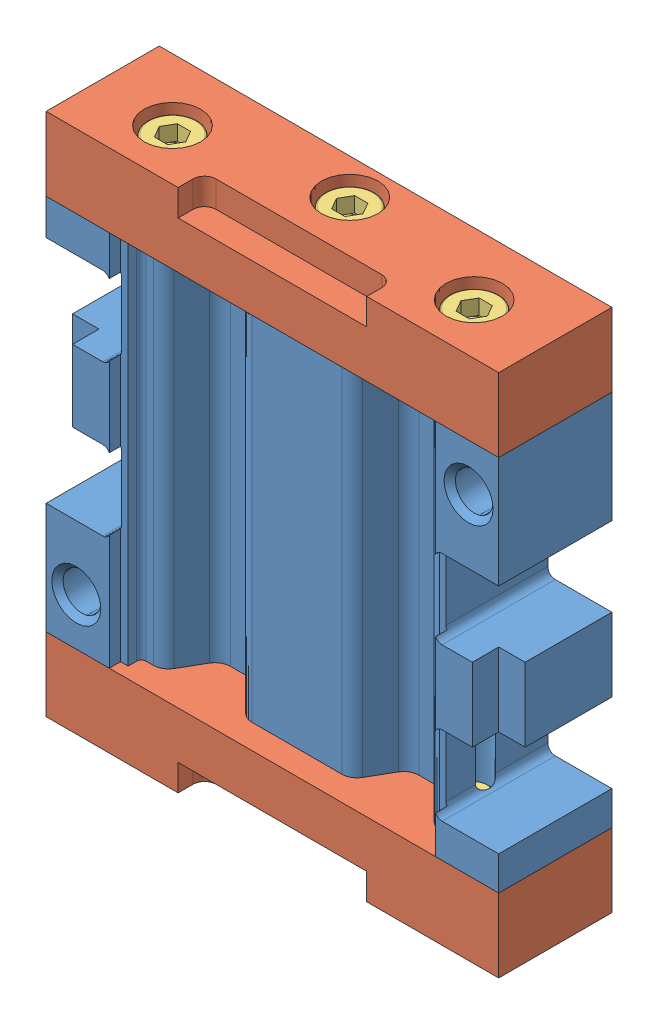
SolidWorks assembly СборкаВерх, configuration По умолчанию. Lengths in mm.
Overall size (120 139 30).
9 component instances, 3 part files, 18 mates.
Components (placement in the parent):
- Пуансон-1: Пуансон [По умолчанию] at origin size (120 100 30)
- БоковинаПуасона-1: БоковинаПуасона [По умолчанию] at (120 100 -30) x (-1 0 0) z (0 0 -1) size (120 19.5 30)
- БоковинаПуасона-3: БоковинаПуасона [По умолчанию] at (0 0 -30) x (1 0 0) z (0 0 -1) size (120 19.5 30)
- socket head cap screw_iso-1: socket head cap screw_iso [ISO 4762 M8 x 16 - 16N] at (100 -17.5 -13.5) x (0 1 0) z (0 0 1) size (24 13 13)
- socket head cap screw_iso-2: socket head cap screw_iso [ISO 4762 M8 x 16 - 16N] at (60 -17.5 -20.5) x (0 1 0) z (0 0 1) size (24 13 13)
- socket head cap screw_iso-3: socket head cap screw_iso [ISO 4762 M8 x 16 - 16N] at (20 -17.5 -13.5) x (0 1 0) z (0 0 1) size (24 13 13)
- socket head cap screw_iso-4: socket head cap screw_iso [ISO 4762 M8 x 16 - 16N] at (20 117.5 -13.5) x (0 -1 0) z (0 0 1) size (24 13 13)
- socket head cap screw_iso-5: socket head cap screw_iso [ISO 4762 M8 x 16 - 16N] at (60 117.5 -20.5) x (0 -1 0) z (0 0 1) size (24 13 13)
- socket head cap screw_iso-6: socket head cap screw_iso [ISO 4762 M8 x 16 - 16N] at (100 117.5 -13.5) x (0 -1 0) z (0 0 1) size (24 13 13)
Mates (geometry in assembly coordinates):
- Совпадение1: coincident anti-aligned: plane of Пуансон-1 through (0 0 0) normal (0 -1 0); plane of БоковинаПуасона-3 through (0 0 -30) normal (0 1 0)
- Совпадение2: coincident anti-aligned: plane of Пуансон-1 through (0 100 0) normal (0 1 0); plane of БоковинаПуасона-1 through (120 100 -30) normal (0 -1 0)
- Концентричный1: concentric aligned: cylinder of Пуансон-1 through (100 77.75 -13.5) axis (0 1 0) radius 4; cylinder of БоковинаПуасона-1 through (100 100 -13.5) axis (0 1 0) radius 4.5
- Концентричный2: concentric aligned: cylinder of Пуансон-1 through (20 77.75 -13.5) axis (0 1 0) radius 4; cylinder of БоковинаПуасона-1 through (20 100 -13.5) axis (0 1 0) radius 4.5
- Концентричный3: concentric aligned: cylinder of Пуансон-1 through (100 22.25 -13.5) axis (0 -1 0) radius 4; cylinder of БоковинаПуасона-3 through (100 0 -13.5) axis (0 -1 0) radius 4.5
- Концентричный4: concentric aligned: cylinder of Пуансон-1 through (20 22.25 -13.5) axis (0 -1 0) radius 4; cylinder of БоковинаПуасона-3 through (20 0 -13.5) axis (0 -1 0) radius 4.5
- Концентричный5: concentric aligned: cylinder of БоковинаПуасона-3 through (100 0 -13.5) axis (0 -1 0) radius 4.5; cylinder of socket head cap screw_iso-1 through (100 -49.25 -13.5) axis (0 -1 0) radius 6.5
- Совпадение3: coincident anti-aligned: plane of БоковинаПуасона-3 through (100 -9.5 -13.5) normal (0 -1 0); plane of socket head cap screw_iso-1 through (93.5 -9.5 -13.5) normal (0 1 0)
- Концентричный6: concentric aligned: cylinder of БоковинаПуасона-3 through (60 0 -20.5) axis (0 -1 0) radius 4.5; cylinder of socket head cap screw_iso-2 through (60 -49.25 -20.5) axis (0 -1 0) radius 6.5
- Совпадение4: coincident anti-aligned: plane of БоковинаПуасона-3 through (60 -9.5 -20.5) normal (0 -1 0); plane of socket head cap screw_iso-2 through (53.5 -9.5 -20.5) normal (0 1 0)
- Концентричный7: concentric aligned: cylinder of БоковинаПуасона-3 through (20 0 -13.5) axis (0 -1 0) radius 4.5; cylinder of socket head cap screw_iso-3 through (20 -49.25 -13.5) axis (0 -1 0) radius 6.5
- Совпадение5: coincident anti-aligned: plane of БоковинаПуасона-3 through (20 -9.5 -13.5) normal (0 -1 0); plane of socket head cap screw_iso-3 through (13.5 -9.5 -13.5) normal (0 1 0)
- Концентричный8: concentric aligned: cylinder of БоковинаПуасона-1 through (20 109.5 -13.5) axis (0 1 0) radius 7.5; cylinder of socket head cap screw_iso-4 through (20 149.25 -13.5) axis (0 1 0) radius 6.5
- Совпадение6: coincident anti-aligned: plane of БоковинаПуасона-1 through (20 109.5 -13.5) normal (0 1 0); plane of socket head cap screw_iso-4 through (26.5 109.5 -13.5) normal (0 -1 0)
- Концентричный9: concentric aligned: cylinder of БоковинаПуасона-1 through (60 100 -20.5) axis (0 1 0) radius 4.5; cylinder of socket head cap screw_iso-5 through (60 149.25 -20.5) axis (0 1 0) radius 6.5
- Совпадение7: coincident anti-aligned: plane of БоковинаПуасона-1 through (60 109.5 -20.5) normal (0 1 0); plane of socket head cap screw_iso-5 through (66.5 109.5 -20.5) normal (0 -1 0)
- Концентричный10: concentric aligned: cylinder of БоковинаПуасона-1 through (100 109.5 -13.5) axis (0 1 0) radius 7.5; cylinder of socket head cap screw_iso-6 through (100 149.25 -13.5) axis (0 1 0) radius 6.5
- Совпадение8: coincident anti-aligned: plane of БоковинаПуасона-1 through (100 109.5 -13.5) normal (0 1 0); plane of socket head cap screw_iso-6 through (106.5 109.5 -13.5) normal (0 -1 0)
